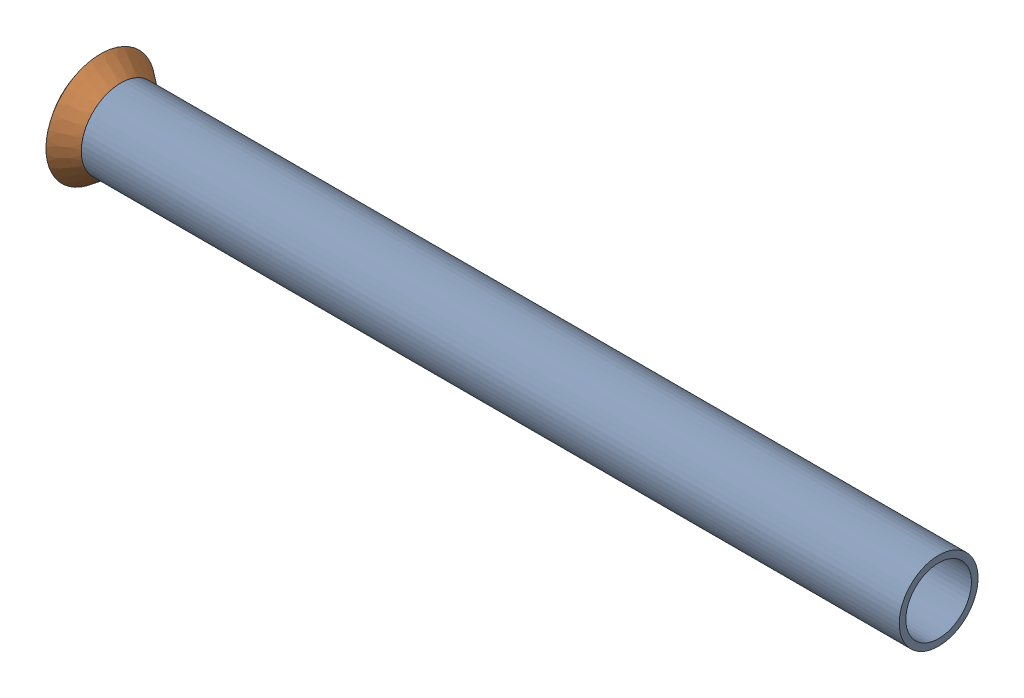
SolidWorks assembly Pipe 54, configuration Default. Lengths in mm.
Overall size (135.69 23.34 23.34).
2 component instances, 2 part files, 1 mates.
Components (placement in the parent):
- part15-1: part15 [Default<As Machined>] at (-669.012 709.1629 -135.0231) x (1 0 0) z (0 -0.924225 -0.381849) size (133.37 12.7 12.7)
- Flared pipe end - .5 inch-1: Flared pipe end - .5 inch [Default<As Machined>] at (-642.2444 453.1219 484.6961) x (0 0.419002 -0.907985) z (-1 0 0) size (17.59 17.59 3.89)
Mates (geometry in assembly coordinates):
- Coincident1697: coincident: cylinder of part15-1 through (-643.8092 453.1219 484.6961) axis (1 0 0) radius 6.35; circle of Flared pipe end - .5 inch-1
